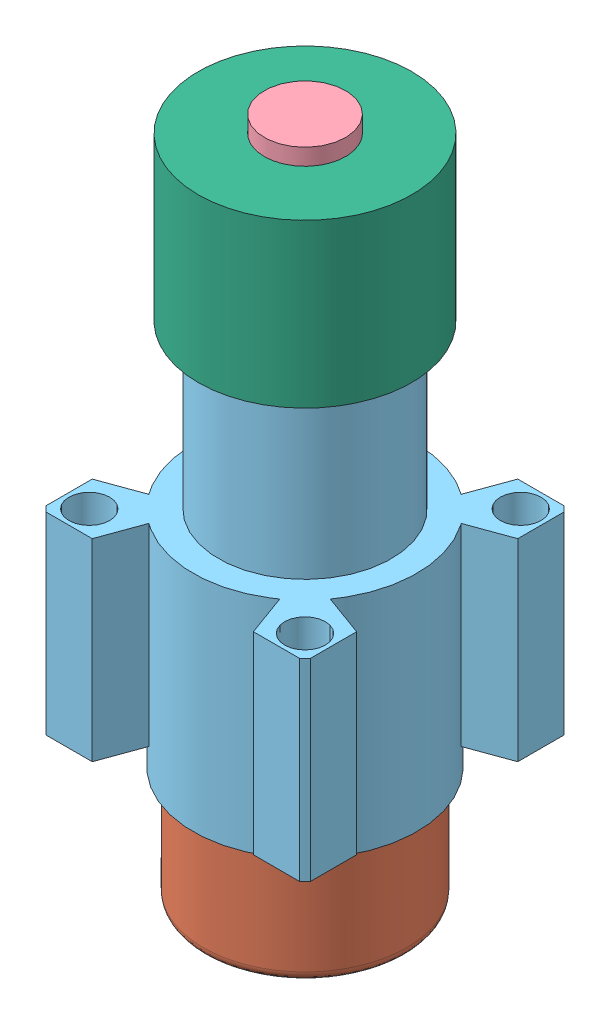
SolidWorks assembly Assemblage6, configuration Défaut. Lengths in mm.
Overall size (28.28 72.17 28.28).
7 component instances, 6 part files, 7 mates.
Components (placement in the parent):
- ressort compressé-1: ressort compressé [Défaut] at (-18.8355 27.8924 39.5618) x (0.989109 0 0.147187) z (0 -1 0) size (11.25 11.25 11)
- Roulette à bille 687-679-modifiée-1: Roulette à bille 687-679-modifiée [Default] at (-13.8605 -30.0008 37.7318) x (0.694238 0 0.719745) z (-0.719745 0 0.694238) size (20 32.17 20)
  - Roulette D20-1: Roulette D20 [Default] at (-2.1367 -5.4811 4.8512) size (20 27 20)
  - bille D12_5-1: bille D12_5 [Default] at (-2.1367 -2.2311 4.8512) x (0.951271 -0.300034 -0.071154) z (0.043636 -0.097448 0.994284) size (12.5 12.5 12.5)
- tige filetée M8-1: tige filetée M8 [Défaut] at (-18.8355 -18.4818 39.5618) x (0.899142 0 -0.437656) z (0.437656 0 0.899142) size (8 50 8)
- alésage porte bille-2: alésage porte bille [Défaut] at (-18.8355 -21.1076 39.5618) size (26 44 26)
- Ecrou réglage hauteur-1: Ecrou réglage hauteur [Défaut] at (-18.8355 32.8924 39.5618) size (21 16 21)
Mates (geometry in assembly coordinates):
- Coaxiale1: concentric aligned: cylinder of Roulette à bille 687-679-modifiée-1/Roulette D20-1; cylinder of tige filetée M8-1
- Coïncidente1: coincident anti-aligned: plane of Roulette à bille 687-679-modifiée-1/Roulette D20-1 through (-18.8355 -18.4818 39.5618) normal (0 1 0); plane of tige filetée M8-1 through (-16.5876 -18.4818 38.4677) normal (0 -1 0)
- Coaxiale3: concentric aligned: cylinder of Roulette à bille 687-679-modifiée-1/Roulette D20-1; cylinder of alésage porte bille-2
- Coaxiale4: concentric anti-aligned: cylinder of ressort compressé-1; cylinder of tige filetée M8-1
- Coaxiale5: concentric anti-aligned: cylinder of tige filetée M8-1; cylinder of Ecrou réglage hauteur-1
- Coïncidente7: coincident anti-aligned: plane of ressort compressé-1 through (-18.8355 27.8924 39.5618) normal (0 1 0); plane of Ecrou réglage hauteur-1 through (-27.3355 27.8924 39.5618) normal (0 -1 0)
- Distance1: distance = 8 mm anti-aligned: plane of Ecrou réglage hauteur-1 through (-27.3355 27.8924 39.5618) normal (0 -1 0); plane of alésage porte bille-2 through (-27.3355 19.8924 39.5618) normal (0 1 0)
